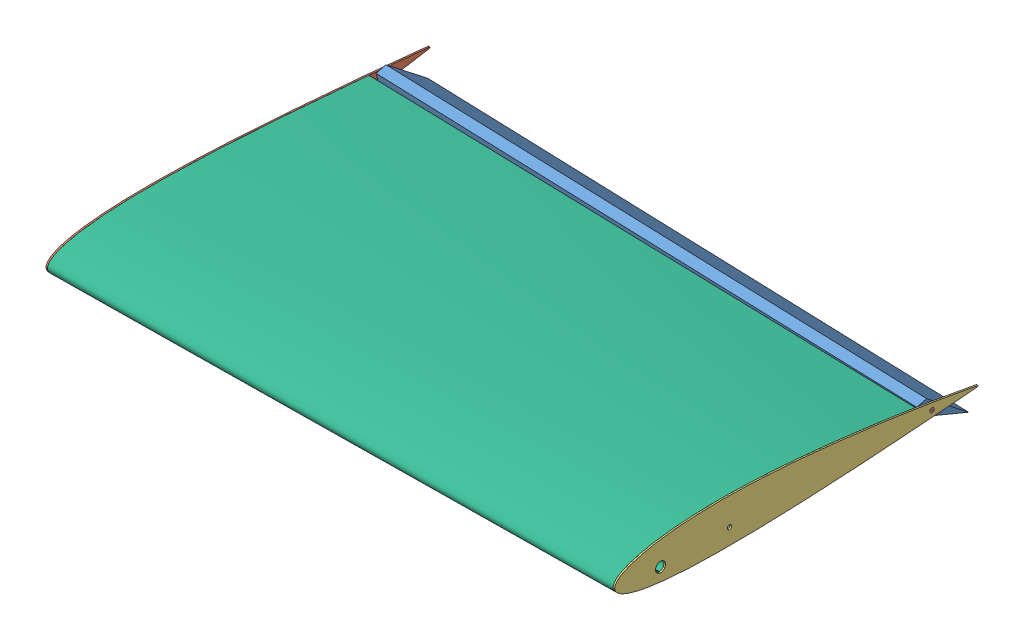
SolidWorks assembly wingAssem_v1c, configuration Default. Lengths in mm.
Overall size (743.66 106.25 524.48).
10 component instances, 6 part files, 28 mates.
Components (placement in the parent):
- wingAileron_v1.1-1: wingAileron_v1.1 [Default] at (371.455 -27.8223 -479.2286) x (0.999844 -0.017077 0.004496) z (0.004746 0.505083 0.863058) size (731.43 18.86 103.73)
- wingAirfoilRib_v1.1-2: wingAirfoilRib_v1.1 [Default] at (-2 0 0) size (2 60.57 503.06)
- wingAirfoilRib_v1.1-3: wingAirfoilRib_v1.1 [Default] at (211 0 0) size (2 60.57 503.06) (suppressed, hidden)
- wingAirfoilRib_v1.1-4: wingAirfoilRib_v1.1 [Default] at (424 0 0) size (2 60.57 503.06) (suppressed, hidden)
- wingAirfoilRib_v1.1-5: wingAirfoilRib_v1.1 [Default] at (637 0 0) size (2 60.57 503.06) (suppressed, hidden)
- wingAirfoilRib_v1.1-6: wingAirfoilRib_v1.1 [Default] at (850 0 0) size (2 60.57 503.06) (suppressed, hidden)
- wingAirfoilRibTip_v1.1-1: wingAirfoilRibTip_v1.1 [Tip] at (739.4215 0 0) size (2 57.39 477.92)
- wingAileronSpar_v1.1-1: wingAileronSpar_v1.1 [Default] at (369.7124 2.5 -427.4838) x (0.009586 0.958579 -0.284665) z (0.999433 0 0.033657) size (5.5 5.5 743.85)
- DS328MG-1: DS328MG [Default] at (232.5 -16 -91) x (0 0 -1) z (1 0 0) size (41 11 31)
- wingBodyNaca1412Twist_v1.2-1: wingBodyNaca1412Twist_v1.2 [Default] at origin size (739.49 93.97 447.47)
Mates (geometry in assembly coordinates):
- Coincident4: coincident aligned: plane of wingBodyNaca1412Twist_v1.2-1 through (0 0 0) normal (1 0 0); plane of assembly through (0 0 0) normal (1 0 0)
- Coincident5: coincident aligned: plane of wingBodyNaca1412Twist_v1.2-1 through (0 0 0) normal (0 1 0); plane of assembly through (0 0 0) normal (0 1 0)
- Coincident6: coincident aligned: plane of wingBodyNaca1412Twist_v1.2-1 through (0 0 0) normal (0 0 1); plane of assembly through (0 0 0) normal (0 0 1)
- Coincident24: coincident anti-aligned: plane of wingBodyNaca1412Twist_v1.2-1 through (0 1.1033 -0.1154) normal (-1 0 0); plane of wingAirfoilRib_v1.1-2 through (0 1.1033 -0.1154) normal (1 0 0)
- Concentric1: concentric aligned: cylinder of wingBodyNaca1412Twist_v1.2-1 through (-7.5482 2.5 -60) axis (1 0 0) radius 9.0689; cylinder of wingAirfoilRib_v1.1-2 through (-2 2.5 -60) axis (1 0 0) radius 9.0689
- Concentric2: concentric aligned: cylinder of wingBodyNaca1412Twist_v1.2-1 through (-7.5482 2.5 -150) axis (1 0 0) radius 2.75; cylinder of wingAirfoilRib_v1.1-2 through (-2 2.5 -150) axis (1 0 0) radius 2.75
- Coincident25: coincident anti-aligned: plane of wingBodyNaca1412Twist_v1.2-1 through (1139.4402 1.0922 -0.1142) normal (1 0 0); plane of wingAirfoilRibTip_v1.1-1 through (1139.4402 1.0922 -0.1142) normal (-1 0 0)
- Concentric3: concentric aligned: cylinder of wingBodyNaca1412Twist_v1.2-1 through (-7.5482 2.5 -60) axis (1 0 0) radius 9.0689; cylinder of wingAirfoilRibTip_v1.1-1 through (1139.4402 2.5 -60) axis (1 0 0) radius 9.0689
- Concentric4: concentric aligned: cylinder of wingBodyNaca1412Twist_v1.2-1 through (-7.5482 2.5 -150) axis (1 0 0) radius 2.75; cylinder of wingAirfoilRibTip_v1.1-1 through (1139.4402 2.5 -150) axis (1 0 0) radius 2.75
- Coincident47: coincident: point of wingAirfoilRib_v1.1-2; plane of wingAileronSpar_v1.1-1 through (-2 2.5 -440.0015) normal (-0.999433 0 -0.033657)
- Coincident50: coincident aligned: line of wingAileronSpar_v1.1-1 through (369.7124 2.5 -427.4838) axis (0.999433 0 0.033657); line of assembly
- Concentric6: concentric aligned: cylinder of wingAileron_v1.1-1 through (738.1289 2.5 -415.0771) axis (-0.999433 0 -0.033657) radius 2.75; cylinder of wingAileronSpar_v1.1-1 through (741.4249 2.5 -414.9661) axis (-0.999433 0 -0.033657) radius 2.75
- Coincident54: coincident anti-aligned: plane of wingAileron_v1.1-1 through (371.455 -27.8223 -479.2286) normal (-0.999433 0 -0.033657); plane of wingAileronSpar_v1.1-1 through (369.7124 2.5 -427.4838) normal (0.999433 0 0.033657)
- Coincident55: coincident anti-aligned: plane of wingBodyNaca1412Twist_v1.2-1 through (245 -20.5826 -70.5) normal (-1 0 0); plane of DS328MG-1 through (245 -15 -105.5) normal (1 0 0)
- Coincident56: coincident anti-aligned: plane of wingBodyNaca1412Twist_v1.2-1 through (0 -15 0) normal (0 -1 0); plane of DS328MG-1 through (232.5 -15 -91) normal (0 1 0)
- Coincident57: coincident anti-aligned: plane of wingBodyNaca1412Twist_v1.2-1 through (200 -20.5826 -70.5) normal (0 0 -1); plane of DS328MG-1 through (223.3095 -15 -70.5) normal (0 0 1)
- Coincident58: coincident aligned: plane of wingBodyNaca1412Twist_v1.2-1 through (0 0 0) normal (0 1 0); plane of assembly through (0 0 0) normal (0 1 0)
- Coincident59: coincident aligned: plane of wingBodyNaca1412Twist_v1.2-1 through (0 0 0) normal (1 0 0); plane of assembly through (0 0 0) normal (1 0 0)
- Coincident60: coincident aligned: plane of wingBodyNaca1412Twist_v1.2-1 through (0 0 0) normal (0 0 1); plane of assembly through (0 0 0) normal (0 0 1)
- Coincident61: coincident anti-aligned: plane of wingAirfoilRibTip_v1.1-1 through (739.4215 9.5989 -0.1599) normal (-1 0 0); plane of wingBodyNaca1412Twist_v1.2-1 through (739.4215 9.5989 -0.1599) normal (1 0 0)
- Coincident62: coincident anti-aligned: plane of wingAirfoilRib_v1.1-2 through (0 -1.3791 -0.1442) normal (1 0 0); plane of wingBodyNaca1412Twist_v1.2-1 through (0 -1.3791 -0.1442) normal (-1 0 0)
- Concentric9: concentric aligned: cylinder of wingAirfoilRib_v1.1-2 through (-2 2.5 -60) axis (1 0 0) radius 6.5625; cylinder of wingBodyNaca1412Twist_v1.2-1 through (-7.5658 2.5 -60) axis (1 0 0) radius 6.5625
- Concentric10: concentric aligned: cylinder of wingAirfoilRib_v1.1-2 through (-2 2.5 -150) axis (1 0 0) radius 2.75; cylinder of wingBodyNaca1412Twist_v1.2-1 through (-7.5658 2.5 -150) axis (1 0 0) radius 2.75
- Concentric11: concentric aligned: cylinder of wingAirfoilRibTip_v1.1-1 through (739.4215 2.5 -60) axis (1 0 0) radius 6.5625; cylinder of wingBodyNaca1412Twist_v1.2-1 through (-7.5658 2.5 -60) axis (1 0 0) radius 6.5625
- Concentric12: concentric aligned: cylinder of wingAirfoilRibTip_v1.1-1 through (739.4215 2.5 -150) axis (1 0 0) radius 2.75; cylinder of wingBodyNaca1412Twist_v1.2-1 through (-7.5658 2.5 -150) axis (1 0 0) radius 2.75
- Coincident63: coincident anti-aligned: plane of DS328MG-1 through (232.5 -5 -91) normal (0 1 0); plane of wingBodyNaca1412Twist_v1.2-1 through (0 -5 0) normal (0 -1 0)
- Coincident64: coincident anti-aligned: plane of DS328MG-1 through (245 -5 -105.5) normal (1 0 0); plane of wingBodyNaca1412Twist_v1.2-1 through (245 -34.6357 -70.5) normal (-1 0 0)
- Coincident65: coincident anti-aligned: plane of DS328MG-1 through (223.3095 -5 -70.5) normal (0 0 1); plane of wingBodyNaca1412Twist_v1.2-1 through (200 -34.6357 -70.5) normal (0 0 -1)
